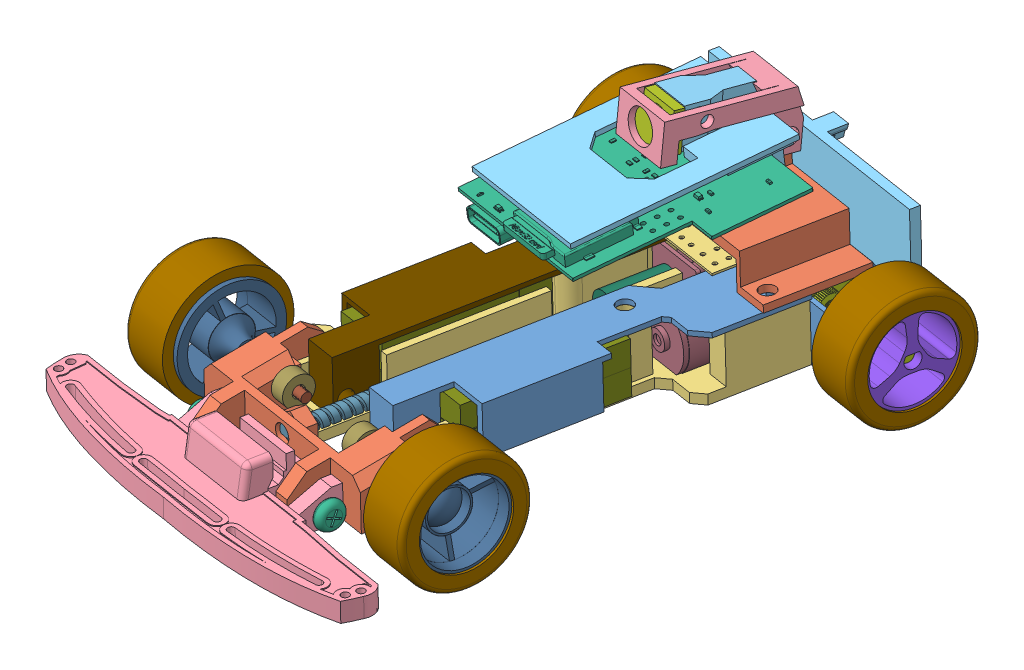
SolidWorks assembly mark3, configuration 默认. Lengths in mm.
Overall size (101.65 53.35 139.29).
38 component instances, 25 part files, 98 mates.
Components (placement in the parent):
- 电机支撑-1: 电机支撑 [默认] at (-55.5379 -28.8213 44.8398) x (0.981589 0.040603 0.186641) z (-0.186874 0.001993 0.982382) size (54.18 11.5 15.42)
- frontwheel-1: frontwheel [默认] at (-52.0282 -29.3617 130.9084) x (0.186874 -0.001993 -0.982382) z (0.981589 0.040603 0.186641) size (26 12.52 42)
- battery-2: battery [默认] at (-46.1812 -28.4253 99.9538) x (0.186874 -0.001993 -0.982382) z (0.981589 0.040603 0.186641) size (77.36 12.2 47.5)
- lead_S1-1: lead_S1 [默认] at (-56.0617 -29.3187 152.1119) x (-0.981589 -0.040603 -0.186641) z (0.186874 -0.001993 -0.982382) size (81.15 10.09 22.16)
- back_lock_2-1: back_lock_2 [默认] at (-35.2625 -20.6322 40.8342) x (0.981589 0.040603 0.186641) z (-0.186874 0.001993 0.982382) size (54 24.45 7.69)
- bolt_3x10-3: bolt_3x10 [默认] at (-37.7203 -26.19 141.7672) x (0.18779 -0.383723 -0.904153) z (-0.034907 -0.922555 0.384283) size (5.6 10.14 5.6)
- bolt_3x10-4: bolt_3x10 [默认] at (-69.5238 -27.5056 135.72) x (-0.161683 0.696876 0.698729) z (-0.101695 -0.716042 0.69061) size (5.6 10.14 5.6)
- N20_MOTOR-1: N20_MOTOR [默认] at (-33.4395 -23.1548 48.887) x (0.981589 0.040603 0.186641) z (-0.186874 0.001993 0.982382) size (33.7 9.7 11.7)
- N20_MOTOR-2: N20_MOTOR [默认] at (-39.702 -23.4138 47.6962) x (-0.981589 -0.040603 -0.186641) z (0.186874 -0.001993 -0.982382) size (33.7 9.7 11.7)
- wheel-1: wheel [默认] at (-9.1942 -22.1519 53.497) x (-0.186874 0.001993 0.982382) z (-0.039516 0.999173 -0.009544) size (19 10.5 19)
- wheel-2: wheel [默认] at (-63.9472 -24.4167 43.0862) x (0.186874 -0.001993 -0.982382) z (-0.039516 0.999173 -0.009544) size (19 10.5 19)
- wheel_black-1: wheel_black [默认] at (-8.2126 -22.1113 53.6836) x (0.038896 -0.999161 0.012798) z (-0.187004 0.005303 0.982345) size (24 10 24)
- wheel_black-2: wheel_black [默认] at (-64.9288 -24.4573 42.8995) x (0.103691 -0.9339 -0.342169) z (0.160411 0.355222 -0.920916) size (24 10 24)
- front_wheel_small-1: front_wheel_small [默认] at (-26.1295 -21.3188 132.2559) x (-0.189297 0.076374 0.978945) z (-0.025493 0.996252 -0.082654) size (20 14.5 20)
- front_wheel_small-2: front_wheel_small [默认] at (-77.1721 -23.4301 122.5506) x (-0.00723 0.984343 -0.176115) z (-0.190869 0.171523 0.966514) size (20 14.5 20)
- 2x20-2: 2x20 [默认] at (-77.1721 -23.4301 122.5506) x (0.168907 0.271731 -0.947435) z (0.981589 0.040603 0.186641) size (2 2 20)
- 2x20-3: 2x20 [默认] at (-45.7612 -22.1308 128.5231) x (0.17078 -0.624182 -0.762385) z (0.981589 0.040603 0.186641) size (2 2 20)
- frontwheellock -single-1: frontwheellock -single [默认] at (-40.9803 -41.9112 134.4714) x (-0.039885 0.999175 -0.007603) z (-0.186796 0.000019 0.982399) size (6 3 6)
- frontwheellock -single-2: frontwheellock -single [默认] at (-64.1706 -2.8375 130.0612) x (0.039885 -0.999175 0.007603) z (-0.186796 0.000019 0.982399) size (6 3 6)
- wheel_black-3: wheel_black [默认] at (-25.1479 -21.2782 132.4426) x (0.19092 -0.237911 -0.952338) z (-0.005736 -0.970438 0.241283) size (24 10 24)
- wheel_black-4: wheel_black [默认] at (-78.1537 -23.4707 122.364) x (-0.040565 0.999169 -0.004021) z (-0.186649 -0.003624 0.98242) size (24 10 24)
- Motor-1: Motor [默认] at (-28.4808 -22.007 69.9321) x (-0.981589 -0.040603 -0.186641) z (0.186874 -0.001993 -0.982382) size (24 10 20.9)
- spiral-1: spiral [默认] at (-53.1294 -22.3587 135.1761) x (0.981589 0.040603 0.186641) z (-0.039516 0.999173 -0.009544) size (3.15 62.2 3)
- Connector-1: Connector [默认] at (-40.0295 -22.4983 66.3111) x (-0.981589 -0.040603 -0.186641) z (-0.039516 0.999173 -0.009544) size (6 12 6)
- li_Battery_big-1: li_Battery_big [默认] at (-55.6896 -27.8869 90.9069) x (0.981589 0.040603 0.186641) z (-0.039516 0.999173 -0.009544) size (11.2 31 5.2)
- li_Battery_big-2: li_Battery_big [默认] at (-55.8951 -22.6912 90.8573) x (0.981589 0.040603 0.186641) z (-0.039516 0.999173 -0.009544) size (11.2 31 5.2)
- li_Battery_big-3: li_Battery_big [默认] at (-35.0762 -27.0342 94.8264) x (0.981589 0.040603 0.186641) z (-0.039516 0.999173 -0.009544) size (11.2 31 5.2)
- li_Battery_big-4: li_Battery_big [默认] at (-35.2817 -21.8385 94.7768) x (0.981589 0.040603 0.186641) z (-0.039516 0.999173 -0.009544) size (11.2 31 5.2)
- switch-1: switch [默认] at (-54.3438 -26.5699 66.0442) x (0.186874 -0.001993 -0.982382) z (0.981589 0.040603 0.186641) size (12 14 6)
- switch-2: switch [默认] at (-60.2333 -26.8135 64.9244) x (0.186874 -0.001993 -0.982382) z (0.981589 0.040603 0.186641) size (12 14 6)
- battery_cover_right-1: battery_cover_right [默认] at (-40.201 -17.3003 66.3625) x (0.186874 -0.001993 -0.982382) z (0.981589 0.040603 0.186641) size (68.55 11 22.03)
- battery_cover_left-2: battery_cover_left [默认] at (-30.4364 -16.8964 68.2192) x (0.186874 -0.001993 -0.982382) z (0.981589 0.040603 0.186641) size (68.55 11 18.11)
- mx1508_shell-1: mx1508_shell [默认] at (-38.3704 -10.3071 57.471) x (0.981589 0.040603 0.186641) z (-0.186874 0.001993 0.982382) size (47.44 18 20)
- MX1508-1: MX1508 [默认] at (-55.559 -12.8312 65.0774) x (0.981589 0.040603 0.186641) z (-0.039516 0.999173 -0.009544) size (29.97 19.56 8.32)
- Camera_Shell-1: Camera_Shell [默认] at (-41.0319 7.7492 69.1751) x (0.016865 -0.991753 0.127053) z (-0.981589 -0.040603 -0.186641) size (12.67 27.2 12)
- K210_board_back_angle_with_cover-1: K210_board_back_angle_with_cover [默认] at (-37.7547 0.7679 50.779) x (0.981589 0.040603 0.186641) z (0.055738 -0.995505 -0.076573) size (26.4 42 16.32)
- Bat_Spectre_K210-1: Bat_Spectre_K210 [默认] at (-24.0811 0.1244 56.0179) x (-0.182693 -0.085566 0.97944) z (0.055738 -0.995505 -0.076573) size (42.67 36.17 7.08)
- Camera-1: Camera [默认] at (-40.4391 7.3704 66.1395) x (0.981589 0.040603 0.186641) z (0.016865 -0.991753 0.127053) size (8 4 8)
Mates (geometry in assembly coordinates):
- 重合48: coincident: plane of frontwheel-1 through (-52.0282 -29.3617 130.9084) normal (0.039516 -0.999173 0.009544); plane of battery-2 through (-46.1417 -29.4244 99.9634) normal (0.039516 -0.999173 0.009544)
- 重合87: coincident: plane of frontwheel-1 through (-52.0282 -29.3617 130.9084) normal (0.039516 -0.999173 0.009544); plane of lead_S1-1 through (-56.0617 -29.3187 152.1119) normal (0.039516 -0.999173 0.009544)
- 重合88: coincident: plane of frontwheel-1 through (-52.0282 -29.3617 130.9084) normal (0.981589 0.040603 0.186641); plane of lead_S1-1 through (-56.0617 -29.3187 152.1119) normal (-0.981589 -0.040603 -0.186641)
- 重合89: coincident: plane of frontwheel-1 through (-53.4763 -16.3625 135.6963) normal (-0.186874 0.001993 0.982382); plane of lead_S1-1 through (-53.2274 -22.6572 135.7564) normal (0.186874 -0.001993 -0.982382)
- 平行41: parallel: plane of frontwheel-1 through (-51.6076 -16.3824 125.8724) normal (0.186874 -0.001993 -0.982382); plane of battery-2 through (-71.4144 -30.2268 120.6058) normal (-0.186874 0.001993 0.982382)
- 重合93: coincident: plane of frontwheel-1 through (-52.0282 -29.3617 130.9084) normal (0.981589 0.040603 0.186641); plane of battery-2 through (-46.1812 -28.4253 99.9538) normal (0.981589 0.040603 0.186641)
- 重合95: coincident: plane of 电机支撑-1 through (-17.4967 -19.8731 44.2122) normal (0.186874 -0.001993 -0.982382); plane of back_lock_2-1 through (-9.1162 -10.5191 45.7874) normal (-0.186874 0.001993 0.982382)
- 重合96: coincident: line of 电机支撑-1 through (-17.2739 -25.5067 44.266) axis (-0.981589 -0.040603 -0.186641); line of back_lock_2-1 through (-8.5377 -25.1453 45.9271) axis (-0.981589 -0.040603 -0.186641)
- 重合97: coincident: plane of lead_S1-1 through (-56.0617 -29.3187 152.1119) normal (-0.981589 -0.040603 -0.186641); plane of back_lock_2-1 through (-35.2625 -20.6322 40.8342) normal (0.981589 0.040603 0.186641)
- 同心35: concentric: cylinder of lead_S1-1 through (-93.4527 -28.4954 131.1701) axis (0.981589 0.040603 0.186641) radius 1.55; cylinder of bolt_3x10-3 through (-45.573 -26.5149 140.2741) axis (-0.981589 -0.040603 -0.186641) radius 1.5
- 重合100: coincident: plane of lead_S1-1 through (-40.4247 -21.9664 155.0716) normal (0.981589 0.040603 0.186641); plane of bolt_3x10-3 through (-37.7203 -26.19 141.7672) normal (-0.981589 -0.040603 -0.186641)
- 同心36: concentric: cylinder of lead_S1-1 through (-13.7913 -25.2002 146.3171) axis (-0.981589 -0.040603 -0.186641) radius 1.55; cylinder of bolt_3x10-4 through (-61.671 -27.1807 137.2132) axis (0.981589 0.040603 0.186641) radius 1.5
- 重合101: coincident: plane of lead_S1-1 through (-72.2282 -23.282 149.0244) normal (-0.981589 -0.040603 -0.186641); plane of bolt_3x10-4 through (-69.5238 -27.5056 135.72) normal (0.981589 0.040603 0.186641)
- 重合102: coincident: plane of 电机支撑-1 through (-55.5379 -28.8213 44.8398) normal (-0.039516 0.999173 -0.009544); plane of N20_MOTOR-1 through (-17.8739 -27.2988 48.2936) normal (0.039516 -0.999173 0.009544)
- 距离11: distance = 1 mm: plane of 电机支撑-1 through (-11.467 -16.925 60.0269) normal (0.186874 -0.001993 -0.982382); plane of N20_MOTOR-1 through (-18.8536 -26.7999 57.6239) normal (-0.186874 0.001993 0.982382)
- 重合104: coincident: plane of 电机支撑-1 through (-9.7591 -28.4289 53.5472) normal (0.981589 0.040603 0.186641); plane of N20_MOTOR-1 through (-8.8097 -26.4933 48.133) normal (0.981589 0.040603 0.186641)
- 重合105: coincident: plane of 电机支撑-1 through (-55.5379 -28.8213 44.8398) normal (-0.039516 0.999173 -0.009544); plane of N20_MOTOR-2 through (-54.8922 -28.762 48.3803) normal (0.039516 -0.999173 0.009544)
- 距离12: distance = 1 mm: plane of N20_MOTOR-2 through (-64.0852 -28.6709 49.0235) normal (-0.186874 0.001993 0.982382); plane of 电机支撑-1 through (-64.6495 -19.1249 49.9147) normal (0.186874 -0.001993 -0.982382)
- 重合107: coincident: plane of 电机支撑-1 through (-62.9614 -30.1292 43.4303) normal (-0.981589 -0.040603 -0.186641); plane of N20_MOTOR-2 through (-63.9917 -28.6719 48.5323) normal (-0.981589 -0.040603 -0.186641)
- 同心40: concentric: cylinder of N20_MOTOR-1 through (-0.3599 -21.7864 55.1768) axis (-0.981589 -0.040603 -0.186641) radius 1.3005; cylinder of wheel-1 through (1.1125 -21.7255 55.4567) axis (-0.981589 -0.040603 -0.186641) radius 1.65
- 平行25: parallel: plane of N20_MOTOR-1 through (-0.5677 -20.8632 56.0689) normal (-0.039516 0.999173 -0.009544); plane of wheel-1 through (1.069 -20.6265 55.4462) normal (0.039516 -0.999173 0.009544)
- 重合113: coincident: plane of N20_MOTOR-1 through (-9.1942 -22.1519 53.497) normal (0.981589 0.040603 0.186641); plane of wheel-1 through (-9.1942 -22.1519 53.497) normal (-0.981589 -0.040603 -0.186641)
- 同心41: concentric: cylinder of N20_MOTOR-2 through (-72.7815 -24.7821 41.4064) axis (0.981589 0.040603 0.186641) radius 1.3005; cylinder of wheel-2 through (-74.2539 -24.843 41.1264) axis (0.981589 0.040603 0.186641) radius 1.65
- 平行26: parallel: plane of N20_MOTOR-2 through (-72.6466 -23.8626 40.4967) normal (-0.039516 0.999173 -0.009544); plane of wheel-2 through (-74.2974 -23.7439 41.1159) normal (0.039516 -0.999173 0.009544)
- 重合115: coincident: plane of N20_MOTOR-2 through (-63.9472 -24.4167 43.0862) normal (-0.981589 -0.040603 -0.186641); plane of wheel-2 through (-63.9472 -24.4167 43.0862) normal (0.981589 0.040603 0.186641)
- 同心42: concentric: cylinder of wheel-1 through (1.1125 -21.7255 55.4567) axis (-0.981589 -0.040603 -0.186641) radius 8.6; circle of N20_MOTOR-1
- 重合117: coincident: plane of wheel-1 through (-8.2126 -22.1113 53.6836) normal (0.981589 0.040603 0.186641); plane of wheel_black-1 through (-8.2126 -22.1113 53.6836) normal (-0.981589 -0.040603 -0.186641)
- 重合118: coincident: plane of wheel-2 through (-64.9288 -24.4573 42.8995) normal (-0.981589 -0.040603 -0.186641); plane of wheel_black-2 through (-64.9288 -24.4573 42.8995) normal (0.981589 0.040603 0.186641)
- 同心43: concentric: cylinder of wheel-2 through (-74.2539 -24.843 41.1264) axis (0.981589 0.040603 0.186641) radius 8.6; cylinder of wheel_black-2 through (-74.7447 -24.8633 41.0331) axis (0.981589 0.040603 0.186641) radius 8.6
- 同心45: concentric: cylinder of frontwheel-1 through (-72.2641 -23.2271 123.4838) axis (0.981589 0.040603 0.186641) radius 1.3; cylinder of 2x20-2 through (-57.5403 -22.618 126.2834) axis (-0.981589 -0.040603 -0.186641) radius 1
- 距离13: distance = 5 mm: plane of 2x20-2 through (-57.5403 -22.618 126.2834) normal (0.981589 0.040603 0.186641); plane of frontwheel-1 through (-63.3394 -16.819 128.7313) normal (0.981589 0.040603 0.186641)
- 同心46: concentric: cylinder of 2x20-2 through (-57.5403 -22.618 126.2834) axis (-0.981589 -0.040603 -0.186641) radius 1; circle of frontwheellock -single-2
- 重合121: coincident: plane of frontwheel-1 through (-63.3394 -16.819 128.7313) normal (0.981589 0.040603 0.186641); plane of frontwheellock -single-2 through (-64.1706 -2.8375 130.0612) normal (-0.981589 -0.040603 -0.186641)
- 同心47: concentric: cylinder of frontwheel-1 through (-72.2641 -23.2271 123.4838) axis (0.981589 0.040603 0.186641) radius 1.3; cylinder of 2x20-3 through (-26.1295 -21.3188 132.2559) axis (-0.981589 -0.040603 -0.186641) radius 1
- 距离14: distance = 5 mm: plane of 2x20-3 through (-45.7612 -22.1308 128.5231) normal (-0.981589 -0.040603 -0.186641); plane of frontwheel-1 through (-41.7445 -15.9258 132.8374) normal (-0.981589 -0.040603 -0.186641)
- 同心48: concentric: cylinder of 2x20-3 through (-26.1295 -21.3188 132.2559) axis (-0.981589 -0.040603 -0.186641) radius 1; cylinder of frontwheellock -single-1 through (-43.7981 -22.0496 128.8964) axis (0.981589 0.040603 0.186641) radius 1.225
- 重合123: coincident: plane of frontwheel-1 through (-41.7445 -15.9258 132.8374) normal (-0.981589 -0.040603 -0.186641); plane of frontwheellock -single-1 through (-40.9803 -41.9112 134.4714) normal (0.981589 0.040603 0.186641)
- 同心50: concentric: cylinder of front_wheel_small-1 through (-21.2215 -21.1157 133.1891) axis (-0.981589 -0.040603 -0.186641) radius 1.1; cylinder of 2x20-3 through (-26.1295 -21.3188 132.2559) axis (-0.981589 -0.040603 -0.186641) radius 1
- 距离17: distance = 1 mm: plane of front_wheel_small-1 through (-30.0278 -22.577 131.6003) normal (-0.981589 -0.040603 -0.186641); plane of frontwheel-1 through (-31.9286 -15.5198 134.7038) normal (0.981589 0.040603 0.186641)
- 同心51: concentric: cylinder of front_wheel_small-2 through (-82.08 -23.6331 121.6174) axis (0.981589 0.040603 0.186641) radius 1.1; cylinder of 2x20-2 through (-57.5403 -22.618 126.2834) axis (-0.981589 -0.040603 -0.186641) radius 1
- 距离18: distance = 1 mm: plane of front_wheel_small-2 through (-73.0358 -23.4564 122.234) normal (0.981589 0.040603 0.186641); plane of frontwheel-1 through (-73.1553 -17.2251 126.8649) normal (-0.981589 -0.040603 -0.186641)
- 同心53: concentric: cylinder of front_wheel_small-1 through (-15.8228 -20.8924 134.2157) axis (-0.981589 -0.040603 -0.186641) radius 9.1283; cylinder of wheel_black-3 through (-15.332 -20.8721 134.309) axis (-0.981589 -0.040603 -0.186641) radius 8.6
- 重合128: coincident: plane of front_wheel_small-1 through (-25.1479 -21.2782 132.4426) normal (0.981589 0.040603 0.186641); plane of wheel_black-3 through (-25.1479 -21.2782 132.4426) normal (-0.981589 -0.040603 -0.186641)
- 同心54: concentric: cylinder of front_wheel_small-2 through (-87.4788 -23.8564 120.5909) axis (0.981589 0.040603 0.186641) radius 9.1283; cylinder of wheel_black-4 through (-87.9696 -23.8767 120.4976) axis (0.981589 0.040603 0.186641) radius 8.6
- 重合129: coincident: plane of front_wheel_small-2 through (-78.1537 -23.4707 122.364) normal (-0.981589 -0.040603 -0.186641); plane of wheel_black-4 through (-78.1537 -23.4707 122.364) normal (0.981589 0.040603 0.186641)
- 重合132: coincident: plane of 电机支撑-1 through (-36.4096 -28.0301 48.4768) normal (0.981589 0.040603 0.186641); plane of battery-2 through (-46.1812 -28.4253 99.9538) normal (0.981589 0.040603 0.186641)
- 重合133: coincident: plane of 电机支撑-1 through (-55.4786 -30.3201 44.8541) normal (0.039516 -0.999173 0.009544); plane of battery-2 through (-46.1417 -29.4244 99.9634) normal (0.039516 -0.999173 0.009544)
- 重合134: coincident: plane of 电机支撑-1 through (-55.9109 -21.3122 52.5994) normal (-0.186874 0.001993 0.982382); plane of battery-2 through (-37.8697 -27.5151 56.0438) normal (0.186874 -0.001993 -0.982382)
- 同心55: concentric: cylinder of wheel-1 through (1.1125 -21.7255 55.4567) axis (-0.981589 -0.040603 -0.186641) radius 8.6; cylinder of wheel_black-1 through (1.6033 -21.7052 55.5501) axis (-0.981589 -0.040603 -0.186641) radius 8.6
- 重合135: coincident: plane of battery-2 through (-46.2207 -27.4261 99.9443) normal (-0.039516 0.999173 -0.009544); plane of Motor-1 through (-28.2832 -27.0029 69.9798) normal (0.039516 -0.999173 0.009544)
- 平行27: parallel: plane of 电机支撑-1 through (-55.9109 -21.3122 52.5994) normal (-0.186874 0.001993 0.982382); plane of Motor-1 through (-43.5063 -27.1478 54.9709) normal (0.186874 -0.001993 -0.982382)
- 同心56: concentric: cylinder of Motor-1 through (-42.5303 -22.4717 79.4579) axis (0.186874 -0.001993 -0.982382) radius 1.5; cylinder of spiral-1 through (-41.6366 -22.4812 74.7596) axis (-0.186874 0.001993 0.982382) radius 1.5
- 重合138: coincident: plane of Motor-1 through (-28.9128 -21.9549 77.1789) normal (-0.186874 0.001993 0.982382); plane of spiral-1 through (-41.6366 -22.4812 74.7596) normal (0.186874 -0.001993 -0.982382)
- 平行28: parallel: plane of Motor-1 through (-43.5548 -21.3939 79.2608) normal (-0.039516 0.999173 -0.009544); plane of Connector-1 through (-41.5759 -21.1835 74.1578) normal (0.039516 -0.999173 0.009544)
- 同心58: concentric: cylinder of spiral-1 through (-41.6366 -22.4812 74.7596) axis (-0.186874 0.001993 0.982382) radius 1.5; cylinder of Connector-1 through (-41.5245 -22.4824 74.1702) axis (0.186874 -0.001993 -0.982382) radius 1.8
- 重合140: coincident: plane of Motor-1 through (-40.0295 -22.4983 66.3111) normal (-0.186874 0.001993 0.982382); plane of Connector-1 through (-40.0295 -22.4983 66.3111) normal (0.186874 -0.001993 -0.982382)
- 重合141: coincident: plane of back_lock_2-1 through (-35.2625 -20.6322 40.8342) normal (0.981589 0.040603 0.186641); plane of spiral-1 through (-53.1294 -22.3587 135.1761) normal (0.981589 0.040603 0.186641)
- 重合142: coincident: plane of 电机支撑-1 through (-55.9109 -21.3122 52.5994) normal (-0.186874 0.001993 0.982382); plane of Motor-1 through (-43.5063 -27.1478 54.9709) normal (0.186874 -0.001993 -0.982382)
- 重合159: coincident: plane of battery-2 through (-46.2207 -27.4261 99.9443) normal (-0.039516 0.999173 -0.009544); plane of li_Battery_big-1 through (-55.6896 -27.8869 90.9069) normal (0.039516 -0.999173 0.009544)
- 平行36: parallel: plane of battery-2 through (-59.963 -27.9945 97.3313) normal (-0.981589 -0.040603 -0.186641); plane of li_Battery_big-1 through (-59.0875 -23.1122 80.9491) normal (-0.981589 -0.040603 -0.186641)
- 重合161: coincident: plane of li_Battery_big-1 through (-60.3108 -23.0044 86.8238) normal (-0.039516 0.999173 -0.009544); plane of li_Battery_big-2 through (-49.3171 -22.5497 88.9141) normal (0.039516 -0.999173 0.009544)
- 重合163: coincident: plane of li_Battery_big-1 through (-59.0875 -23.1122 80.9491) normal (-0.981589 -0.040603 -0.186641); plane of li_Battery_big-2 through (-59.293 -17.9165 80.8995) normal (-0.981589 -0.040603 -0.186641)
- 重合164: coincident: plane of li_Battery_big-1 through (-64.8806 -23.0505 111.4029) normal (-0.186874 0.001993 0.982382); plane of li_Battery_big-2 through (-65.0861 -17.8548 111.3533) normal (-0.186874 0.001993 0.982382)
- 重合165: coincident: plane of battery-2 through (-62.9569 -21.9701 111.7667) normal (0.186874 -0.001993 -0.982382); plane of li_Battery_big-1 through (-64.8806 -23.0505 111.4029) normal (-0.186874 0.001993 0.982382)
- 重合166: coincident: plane of battery-2 through (-46.2207 -27.4261 99.9443) normal (-0.039516 0.999173 -0.009544); plane of li_Battery_big-3 through (-35.0762 -27.0342 94.8264) normal (0.039516 -0.999173 0.009544)
- 平行39: parallel: plane of battery-2 through (-32.4785 -26.8576 102.5573) normal (0.981589 0.040603 0.186641); plane of li_Battery_big-3 through (-27.6767 -21.813 86.9216) normal (0.981589 0.040603 0.186641)
- 重合168: coincident: plane of li_Battery_big-3 through (-39.6975 -22.1518 90.7432) normal (-0.039516 0.999173 -0.009544); plane of li_Battery_big-4 through (-28.7037 -21.697 92.8336) normal (0.039516 -0.999173 0.009544)
- 重合169: coincident: plane of li_Battery_big-3 through (-27.6767 -21.813 86.9216) normal (0.981589 0.040603 0.186641); plane of li_Battery_big-4 through (-27.8821 -16.6172 86.872) normal (0.981589 0.040603 0.186641)
- 重合170: coincident: plane of li_Battery_big-3 through (-44.2672 -22.1978 115.3224) normal (-0.186874 0.001993 0.982382); plane of li_Battery_big-4 through (-44.4727 -17.0021 115.2728) normal (-0.186874 0.001993 0.982382)
- 重合171: coincident: plane of battery-2 through (-35.4724 -20.8332 116.9926) normal (0.186874 -0.001993 -0.982382); plane of li_Battery_big-3 through (-44.2672 -22.1978 115.3224) normal (-0.186874 0.001993 0.982382)
- 重合172: coincident: plane of battery-2 through (-54.2807 -18.6067 113.6254) normal (-0.981589 -0.040603 -0.186641); plane of li_Battery_big-2 through (-48.4955 -17.4699 82.9525) normal (0.981589 0.040603 0.186641)
- 重合173: coincident: plane of battery-2 through (-44.4648 -18.2007 115.4918) normal (0.981589 0.040603 0.186641); plane of li_Battery_big-4 through (-38.6796 -17.0639 84.8189) normal (-0.981589 -0.040603 -0.186641)
- 重合174: coincident: plane of battery-2 through (-46.28 -25.9273 99.93) normal (-0.039516 0.999173 -0.009544); plane of switch-1 through (-54.3438 -26.5699 66.0442) normal (0.039516 -0.999173 0.009544)
- 重合176: coincident: plane of battery-2 through (-52.5203 -26.4361 72.4984) normal (-0.186874 0.001993 0.982382); plane of switch-1 through (-52.7179 -21.4403 72.4507) normal (-0.186874 0.001993 0.982382)
- 重合177: coincident: plane of battery-2 through (-57.6823 -17.6919 97.7443) normal (-0.981589 -0.040603 -0.186641); plane of switch-1 through (-50.4754 -21.4642 60.6621) normal (0.981589 0.040603 0.186641)
- 重合178: coincident: plane of battery-2 through (-46.28 -25.9273 99.93) normal (-0.039516 0.999173 -0.009544); plane of switch-2 through (-60.2333 -26.8135 64.9244) normal (0.039516 -0.999173 0.009544)
- 重合180: coincident: plane of switch-1 through (-56.3649 -21.7078 59.5423) normal (-0.981589 -0.040603 -0.186641); plane of switch-2 through (-56.3649 -21.7078 59.5423) normal (0.981589 0.040603 0.186641)
- 重合181: coincident: plane of switch-1 through (-52.7179 -21.4403 72.4507) normal (-0.186874 0.001993 0.982382); plane of switch-2 through (-58.6074 -21.6839 71.3309) normal (-0.186874 0.001993 0.982382)
- 重合184: coincident: plane of battery-2 through (-46.6238 -17.2345 99.847) normal (-0.039516 0.999173 -0.009544); plane of battery_cover_right-1 through (-40.201 -17.3003 66.3625) normal (0.039516 -0.999173 0.009544)
- 同心59: concentric: circle of battery-2; circle of battery_cover_right-1
- 平行40: parallel: plane of li_Battery_big-2 through (-65.0861 -17.8548 111.3533) normal (-0.186874 0.001993 0.982382); plane of battery_cover_right-1 through (-55.5448 -27.3806 122.4627) normal (-0.186874 0.001993 0.982382)
- 同心60: concentric: cylinder of frontwheel-1 through (-70.9704 -25.2384 117.1174) axis (0.981589 0.040603 0.186641) radius 1.5; cylinder of battery-2 through (-74.0928 -25.3675 116.5237) axis (0.981589 0.040603 0.186641) radius 1.55
- 重合185: coincident: plane of battery-2 through (-44.4648 -18.2007 115.4918) normal (0.981589 0.040603 0.186641); plane of battery_cover_left-2 through (-46.4579 -15.9822 125.4915) normal (-0.981589 -0.040603 -0.186641)
- 重合186: coincident: plane of battery_cover_right-1 through (-55.5448 -27.3806 122.4627) normal (-0.186874 0.001993 0.982382); plane of battery_cover_left-2 through (-45.7803 -26.9767 124.3194) normal (-0.186874 0.001993 0.982382)
- 同心61: concentric: circle of frontwheel-1; circle of battery_cover_left-2
- 重合187: coincident: plane of battery_cover_left-2 through (-30.476 -15.8973 68.2096) normal (-0.039516 0.999173 -0.009544); plane of mx1508_shell-1 through (-38.1333 -16.3021 57.5283) normal (0.039516 -0.999173 0.009544)
- 平行42: parallel: plane of battery_cover_left-2 through (-23.5885 -15.7153 58.7366) normal (0.186874 -0.001993 -0.982382); plane of mx1508_shell-1 through (-39.851 -8.2938 64.8198) normal (-0.186874 0.001993 0.982382)
- 平行49: parallel: plane of mx1508_shell-1 through (-38.3704 -10.3071 57.471) normal (0.039516 -0.999173 0.009544); plane of MX1508-1 through (-55.6302 -12.8305 65.4517) normal (-0.039516 0.999173 -0.009544)
- 平行44: parallel: plane of mx1508_shell-1 through (-39.851 -8.2938 64.8198) normal (-0.186874 0.001993 0.982382); line of MX1508-1 through (-26.2101 -11.6135 71.0457) axis (-0.981589 -0.040603 -0.186641)
- 同心62: concentric: circle of mx1508_shell-1; circle of Camera_Shell-1
- 重合192: coincident: plane of mx1508_shell-1 through (-38.9154 1.6072 49.7087) normal (-0.981589 -0.040603 -0.186641); plane of Camera_Shell-1 through (-38.7753 -3.5666 50.0974) normal (0.981589 0.040603 0.186641)
- 同心63: concentric: cylinder of Camera_Shell-1 through (-45.8123 8.6813 61.9661) axis (0.981589 0.040603 0.186641) radius 1.2; cylinder of K210_board_back_angle_with_cover-1 through (-46.3031 8.661 61.8728) axis (0.981589 0.040603 0.186641) radius 1.2818
- 平行45: parallel: plane of Camera_Shell-1 through (-33.7801 10.8804 62.5019) normal (-0.016865 0.991753 -0.127053); plane of K210_board_back_angle_with_cover-1 through (-38.5026 11.3926 65.7959) normal (-0.016865 0.991753 -0.127053)
- 重合194: coincident: plane of Camera_Shell-1 through (-45.2588 7.445 67.361) normal (0.981589 0.040603 0.186641); plane of K210_board_back_angle_with_cover-1 through (-45.4335 -26.1334 75.5843) normal (-0.981589 -0.040603 -0.186641)
- 平行47: parallel: plane of K210_board_back_angle_with_cover-1 through (-50.9128 3.3558 57.4793) normal (0.055738 -0.995505 -0.076573); plane of Bat_Spectre_K210-1 through (-40.0208 1.6472 58.881) normal (-0.055738 0.995505 0.076573)
- 平行46: parallel: line of K210_board_back_angle_with_cover-1 through (-58.6495 1.3668 89.8155) axis (0.182693 0.085566 -0.97944); line of Bat_Spectre_K210-1 through (-61.5625 -3.9442 89.7752) axis (0.182693 0.085566 -0.97944)
- 同心64: concentric: cylinder of Camera_Shell-1 through (-41.4125 7.9924 71.1235) axis (0.19026 -0.121566 -0.974178) radius 3.25; circle of Camera-1
- 平行48: parallel: plane of Camera_Shell-1 through (-33.7801 10.8804 62.5019) normal (-0.016865 0.991753 -0.127053); line of Camera-1 through (-36.9607 11.743 68.3262) axis (-0.981589 -0.040603 -0.186641)
